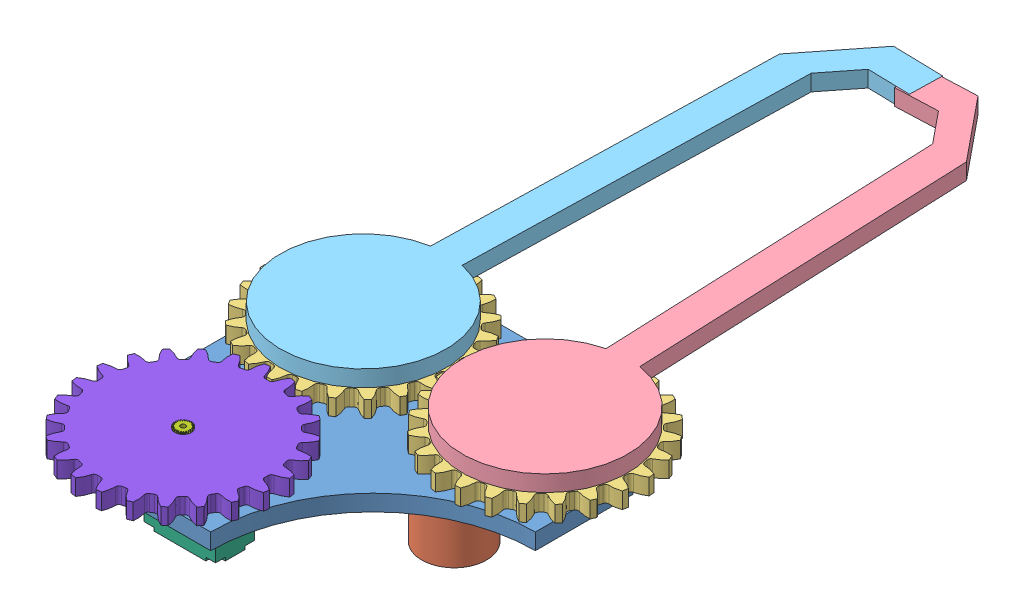
SolidWorks assembly Ensamblaje1, configuration Predeterminado. Lengths in mm.
Overall size (126.17 50 247.4).
10 component instances, 8 part files, 20 mates.
Components (placement in the parent):
- base-3: base [Predeterminado] at (78 2.5 20.5817) x (1 0 0) z (0 1 0) size (100 100 8)
- Extensor.-1: Extensor. [Predeterminado] at (78 -17.5 20.5817) x (0.526408 0 0.850232) z (0 -1 0) size (20 20 35)
- Engrane 1 - 2 G-1: Engrane 1 - 2 G [Predeterminado] at (50 7.5 20.5817) x (-0.023951 0 0.999713) z (0 -1 0) size (59.97 59.97 5)
- Pinza 1-1: Pinza 1 [Predeterminado] at (102.8212 15 -56.8556) x (-0.041015 0 -0.999159) z (0 -1 0) size (175.5 51 15)
- Pinza 2-1: Pinza 2 [Predeterminado] at (51.8563 10 -56.8985) x (0.023951 0 -0.999713) z (0 1 0) size (175.5 51 15)
- Engrane 1 - 2 G-2: Engrane 1 - 2 G [Predeterminado] at (106 7.5 20.5817) x (-0.041015 0 -0.999159) z (0 -1 0) size (59.97 59.97 5)
- SG-90-1: SG-90 [Predeterminado] at (51.3131 -48 78.7222) x (-1 0 0) z (0 0 -1) size (32 26.5 12)
  - Pieza1-1: Pieza1 [Predeterminado] at (-4.6869 32 1.6404) size (32 21.5 12)
  - PZ2-1: PZ2 [Predeterminado] at (0.3131 58.5 1.6404) x (0.702574 0 -0.71161) z (0.71161 0 0.702574) size (4.99 10 4.99)
- Engrane M-3: Engrane M [Predeterminado] at (51 7.5 77.0817) x (0.902283 0 -0.431144) z (0 1 0) size (59.97 59.97 5)
Mates (geometry in assembly coordinates):
- Paralelo1: parallel: plane of assembly; plane of assembly; plane of Pinza 1-1 through (106 15 20.5817) normal (0 1 0); plane of Pinza 2-1 through (50 15 20.5817) normal (0 1 0)
- Concéntrica4: concentric: cylinder of assembly; cylinder of assembly; cylinder of Pinza 1-1 through (118.4895 5 20.069) axis (0 1 0) radius 2.5; cylinder of Engrane 1 - 2 G-2 through (118.4895 10 20.069) axis (0 -1 0) radius 2.5
- Concéntrica5: concentric: cylinder of assembly; cylinder of assembly; cylinder of Pinza 1-1 through (106 0 20.5817) axis (0 1 0) radius 5; cylinder of Engrane 1 - 2 G-2 through (106 10 20.5817) axis (0 -1 0) radius 5
- Coincidente9: coincident: plane of assembly; plane of assembly; plane of Pinza 1-1 through (106 10 20.5817) normal (0 -1 0); plane of Engrane 1 - 2 G-2 through (106 10 20.5817) normal (0 1 0)
- Concéntrica7: concentric: cylinder of assembly; cylinder of assembly; cylinder of Engrane 1 - 2 G-1 through (37.5036 10 20.2823) axis (0 -1 0) radius 2.5; cylinder of Pinza 2-1 through (37.5036 5 20.2823) axis (0 1 0) radius 2.5
- Coincidente12: coincident: plane of assembly; plane of assembly; plane of Engrane 1 - 2 G-1 through (50 10 20.5817) normal (0 1 0); plane of Pinza 2-1 through (50 10 20.5817) normal (0 -1 0)
- Concéntrica11: concentric: cylinder of assembly; cylinder of assembly; cylinder of Engrane 1 - 2 G-1 through (50 10 20.5817) axis (0 -1 0) radius 5; cylinder of Pinza 2-1 through (50 0 20.5817) axis (0 1 0) radius 5
- Relación de posición de engranaje1: gear = 24 : 24 mm: cylinder of assembly; cylinder of assembly; cylinder of Pinza 1-1 through (106 0 20.5817) axis (0 1 0) radius 5; cylinder of Pinza 2-1 through (50 0 20.5817) axis (0 1 0) radius 5
- Concéntrica12: concentric: cylinder of assembly; cylinder of assembly; cylinder of base-3 through (50 5 20.5817) axis (0 -1 0) radius 5; cylinder of Pinza 2-1 through (50 0 20.5817) axis (0 1 0) radius 5
- Concéntrica13: concentric: cylinder of assembly; cylinder of assembly; cylinder of base-3 through (106 5 20.5817) axis (0 -1 0) radius 5; cylinder of Pinza 1-1 through (106 0 20.5817) axis (0 1 0) radius 5
- Coincidente13: coincident: plane of assembly; plane of assembly; plane of Pinza 1-1 through (106 15 20.5817) normal (0 1 0); plane of Pinza 2-1 through (50 15 20.5817) normal (0 1 0)
- Coincidente14: coincident: plane of assembly; plane of assembly; plane of base-3 through (128 5 95.5817) normal (0 1 0); plane of Engrane 1 - 2 G-2 through (106 5 20.5817) normal (0 -1 0)
- Concéntrica14: concentric: cylinder of assembly; cylinder of assembly; cylinder of base-3 through (78 5 20.5817) axis (0 -1 0) radius 2.5; cylinder of Extensor.-1 through (78 -35 20.5817) axis (0 1 0) radius 2.5
- Coincidente15: coincident: plane of assembly; plane of assembly; plane of base-3 through (128 0 95.5817) normal (0 -1 0); plane of Extensor.-1 through (78 0 20.5817) normal (0 1 0)
- Coincidente16: coincident: plane of base-3 through (44 5 83.0817) normal (0 0 -1); plane of SG-90-1/Pieza1-1 through (45 -5 83.0817) normal (0 0 1)
- Coincidente17: coincident: plane of base-3 through (67 5 83.0817) normal (-1 0 0); plane of SG-90-1/Pieza1-1 through (67 1 83.0817) normal (1 0 0)
- Coincidente18: coincident: plane of base-3 through (78 -3 20.5817) normal (0 -1 0); plane of SG-90-1/Pieza1-1 through (56 -3 77.0817) normal (0 1 0)
- Coincidente19: coincident: plane of assembly; plane of assembly; plane of base-3 through (128 5 95.5817) normal (0 1 0); plane of Engrane M-3 through (51 5 77.0817) normal (0 -1 0)
- Concéntrica15: concentric: cylinder of assembly; cylinder of assembly; cylinder of SG-90-1/PZ2-1 through (51 0.5 77.0817) axis (0 1 0) radius 2.5; cylinder of Engrane M-3 through (51 5 77.0817) axis (0 1 0) radius 2.5
- Relación de posición de engranaje2: gear = 24 : 24 mm: cylinder of assembly; cylinder of assembly; cylinder of Engrane M-3 through (51 5 77.0817) axis (0 1 0) radius 2.5; cylinder of Engrane 1 - 2 G-1 through (50 10 20.5817) axis (0 -1 0) radius 5
